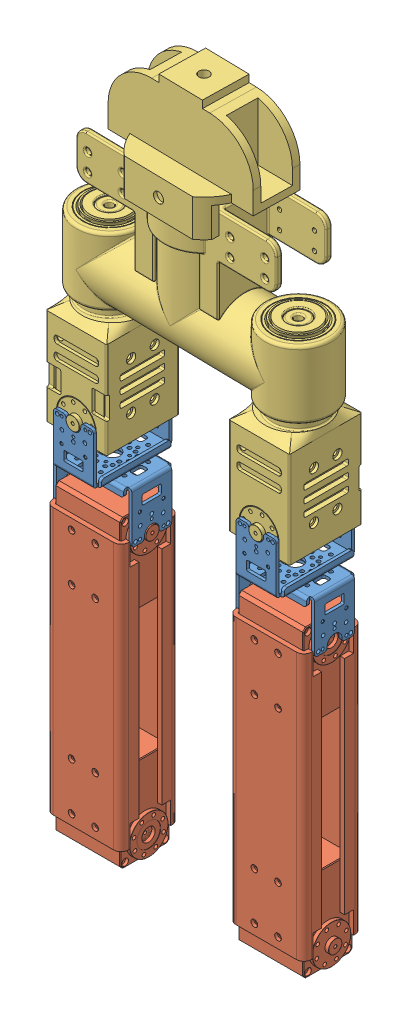
SolidWorks assembly Assem1, configuration Default. Lengths in mm.
Overall size (180.86 486.77 137.4).
5 component instances, 3 part files, 8 mates.
Components (placement in the parent):
- model_part_LINK-1: model_part_LINK [Default] at (-113.1556 -56.8734 -86.9554) x (0.999827 0 0.018597) z (-0.018597 0 0.999827) size (53.49 69 53.49)
- model_part_THIGH-1: model_part_THIGH [Default] at (257.7392 -39.4496 48.3825) x (-0.999827 -0.00471 -0.01799) z (0.018597 -0.253243 -0.967224) size (53.32 206.27 84.55)
- model_part_WAIST-1: model_part_WAIST [Default] at (-113.1556 -56.8734 -86.9554) x (0.999827 0 0.018597) z (-0.018597 0 0.999827) size (176.79 236.92 60.38)
- model_part_LINK-2: model_part_LINK [Default] at (12.8219 -56.8734 -84.5378) x (0.999827 0 0.018597) z (-0.018597 0 0.999827) size (53.49 69 53.49)
- model_part_THIGH-2: model_part_THIGH [Default] at (-239.1332 -39.4496 -117.0682) x (0.999827 -0.00471 0.01799) z (-0.018597 -0.253243 0.967224) size (53.32 206.27 84.55)
Mates (geometry in assembly coordinates):
- Concentric1: concentric anti-aligned: circle of model_part_LINK-1; circle of model_part_WAIST-1
- Coincident1: coincident anti-aligned: plane of model_part_LINK-1 through (-67.1857 93.3991 -60.0516) normal (0 0 1); plane of model_part_WAIST-1 through (-53.6857 123.3991 -60.0516) normal (0 0 -1)
- Concentric2: concentric anti-aligned: circle of model_part_LINK-1; circle of model_part_THIGH-2
- Coincident2: coincident anti-aligned: plane of model_part_LINK-1 through (-78.1857 89.3991 -49.0516) normal (1 0 0); plane of model_part_THIGH-2 through (-78.1857 59.3991 -35.5516) normal (-1 0 0)
- Concentric3: concentric anti-aligned: circle of model_part_WAIST-1; circle of model_part_LINK-2
- Coincident3: coincident anti-aligned: plane of model_part_WAIST-1 through (72.2918 123.3991 -57.6341) normal (0 0 -1); plane of model_part_LINK-2 through (58.7918 93.3991 -57.6341) normal (0 0 1)
- Concentric4: concentric anti-aligned: circle of model_part_THIGH-1; circle of model_part_LINK-2
- Coincident4: coincident anti-aligned: plane of model_part_THIGH-1 through (47.7918 59.3991 -33.1341) normal (-1 0 0); plane of model_part_LINK-2 through (47.7918 89.3991 -46.6341) normal (1 0 0)
